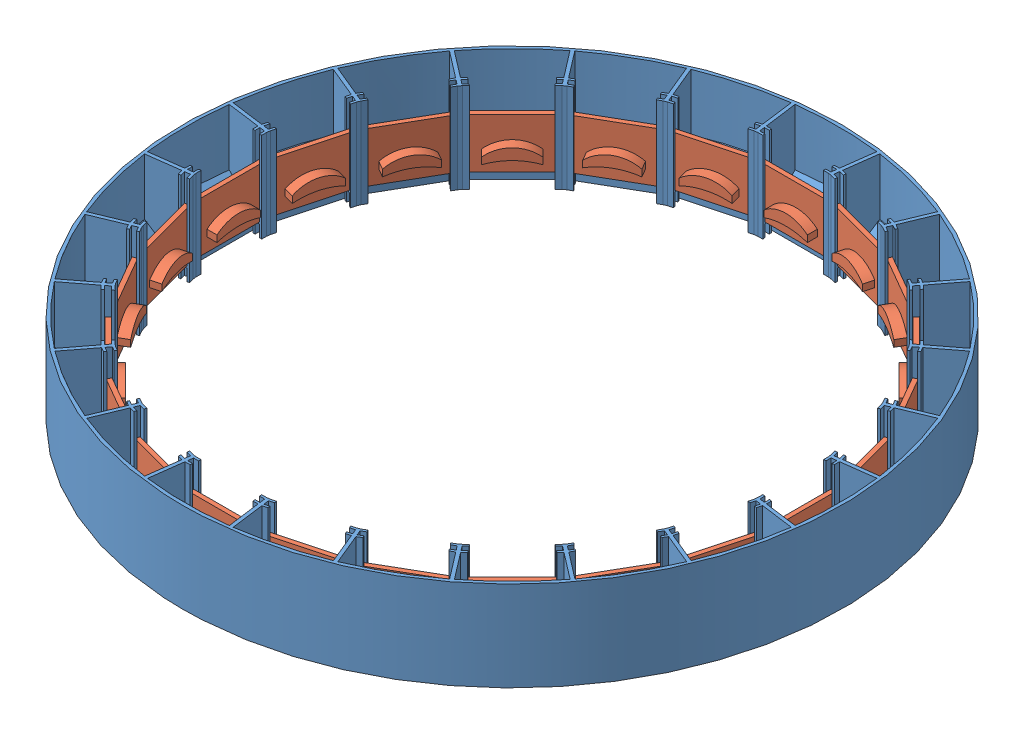
SolidWorks assembly Montagem_andar, configuration Valor predeterminado. Lengths in mm.
Overall size (198 27 198).
25 component instances, 2 part files, 3 mates.
Components (placement in the parent):
- Andar-2: Andar [Valor predeterminado] at origin size (198 27 198)
- Porta3-1: Porta3 [Valor predeterminado] at (-0.0029 3.9912 2.4087) x (1 0 0.000196) z (-0.000196 0 1) size (21.35 15 4.32)
- Porta3-2: Porta3 [Valor predeterminado] at (0.6206 3.9912 2.3274) x (0.965976 0 -0.25863) z (0.25863 0 0.965976) size (21.35 15 4.32)
- Porta3-3: Porta3 [Valor predeterminado] at (1.2019 3.9912 2.0875) x (0.866123 0 -0.49983) z (0.49983 0 0.866123) size (21.35 15 4.32)
- Porta3-4: Porta3 [Valor predeterminado] at (1.7012 3.9912 1.7053) x (0.707245 0 -0.706968) z (0.706968 0 0.707245) size (21.35 15 4.32)
- Porta3-5: Porta3 [Valor predeterminado] at (2.0846 3.9912 1.2069) x (0.50017 0 -0.865927) z (0.865927 0 0.50017) size (21.35 15 4.32)
- Porta3-6: Porta3 [Valor predeterminado] at (2.3259 3.9912 0.6262) x (0.259008 0 -0.965875) z (0.965875 0 0.259008) size (21.35 15 4.32)
- Porta3-7: Porta3 [Valor predeterminado] at (2.4087 3.9912 0.0029) x (0.000196 0 -1) z (1 0 0.000196) size (21.35 15 4.32)
- Porta3-8: Porta3 [Valor predeterminado] at (2.3274 3.9912 -0.6206) x (-0.25863 0 -0.965976) z (0.965976 0 -0.25863) size (21.35 15 4.32)
- Porta3-9: Porta3 [Valor predeterminado] at (2.0875 3.9912 -1.2019) x (-0.49983 0 -0.866123) z (0.866123 0 -0.49983) size (21.35 15 4.32)
- Porta3-10: Porta3 [Valor predeterminado] at (1.7053 3.9912 -1.7012) x (-0.706968 0 -0.707245) z (0.707245 0 -0.706968) size (21.35 15 4.32)
- Porta3-11: Porta3 [Valor predeterminado] at (1.2069 3.9912 -2.0846) x (-0.865927 0 -0.50017) z (0.50017 0 -0.865927) size (21.35 15 4.32)
- Porta3-12: Porta3 [Valor predeterminado] at (0.6262 3.9912 -2.3259) x (-0.965875 0 -0.259008) z (0.259008 0 -0.965875) size (21.35 15 4.32)
- Porta3-13: Porta3 [Valor predeterminado] at (0.0029 3.9912 -2.4087) x (-1 0 -0.000196) z (0.000196 0 -1) size (21.35 15 4.32)
- Porta3-14: Porta3 [Valor predeterminado] at (-0.6206 3.9912 -2.3274) x (-0.965976 0 0.25863) z (-0.25863 0 -0.965976) size (21.35 15 4.32)
- Porta3-15: Porta3 [Valor predeterminado] at (-1.2019 3.9912 -2.0875) x (-0.866123 0 0.49983) z (-0.49983 0 -0.866123) size (21.35 15 4.32)
- Porta3-16: Porta3 [Valor predeterminado] at (-1.7012 3.9912 -1.7053) x (-0.707245 0 0.706968) z (-0.706968 0 -0.707245) size (21.35 15 4.32)
- Porta3-17: Porta3 [Valor predeterminado] at (-2.0846 3.9912 -1.2069) x (-0.50017 0 0.865927) z (-0.865927 0 -0.50017) size (21.35 15 4.32)
- Porta3-18: Porta3 [Valor predeterminado] at (-2.3259 3.9912 -0.6262) x (-0.259008 0 0.965875) z (-0.965875 0 -0.259008) size (21.35 15 4.32)
- Porta3-19: Porta3 [Valor predeterminado] at (-2.4087 3.9912 -0.0029) x (-0.000196 0 1) z (-1 0 -0.000196) size (21.35 15 4.32)
- Porta3-20: Porta3 [Valor predeterminado] at (-2.3274 3.9912 0.6206) x (0.25863 0 0.965976) z (-0.965976 0 0.25863) size (21.35 15 4.32)
- Porta3-21: Porta3 [Valor predeterminado] at (-2.0875 3.9912 1.2019) x (0.49983 0 0.866123) z (-0.866123 0 0.49983) size (21.35 15 4.32)
- Porta3-22: Porta3 [Valor predeterminado] at (-1.7053 3.9912 1.7012) x (0.706968 0 0.707245) z (-0.707245 0 0.706968) size (21.35 15 4.32)
- Porta3-23: Porta3 [Valor predeterminado] at (-1.2069 3.9912 2.0846) x (0.865927 0 0.50017) z (-0.50017 0 0.865927) size (21.35 15 4.32)
- Porta3-24: Porta3 [Valor predeterminado] at (-0.6262 3.9912 2.3259) x (0.965875 0 0.259008) z (-0.259008 0 0.965875) size (21.35 15 4.32)
Mates (geometry in assembly coordinates):
- Coincidente2: coordinate: point of Andar-2; point of assembly
- Distância1: distance = 0.1 mm: plane of Andar-2 through (-9.1902 4 -85.0306) normal (0 0 -1); plane of Porta3-1 through (-10.5016 18.9912 -85.1306) normal (0 0 1)
- Distância3: distance = 0.2 mm: line of Porta3-1 through (-10.5016 18.9912 -85.1306) axis (0 -1 0); plane of Andar-2 through (-10.7293 27 -85.3281) normal (0.991445 0 -0.130526)
